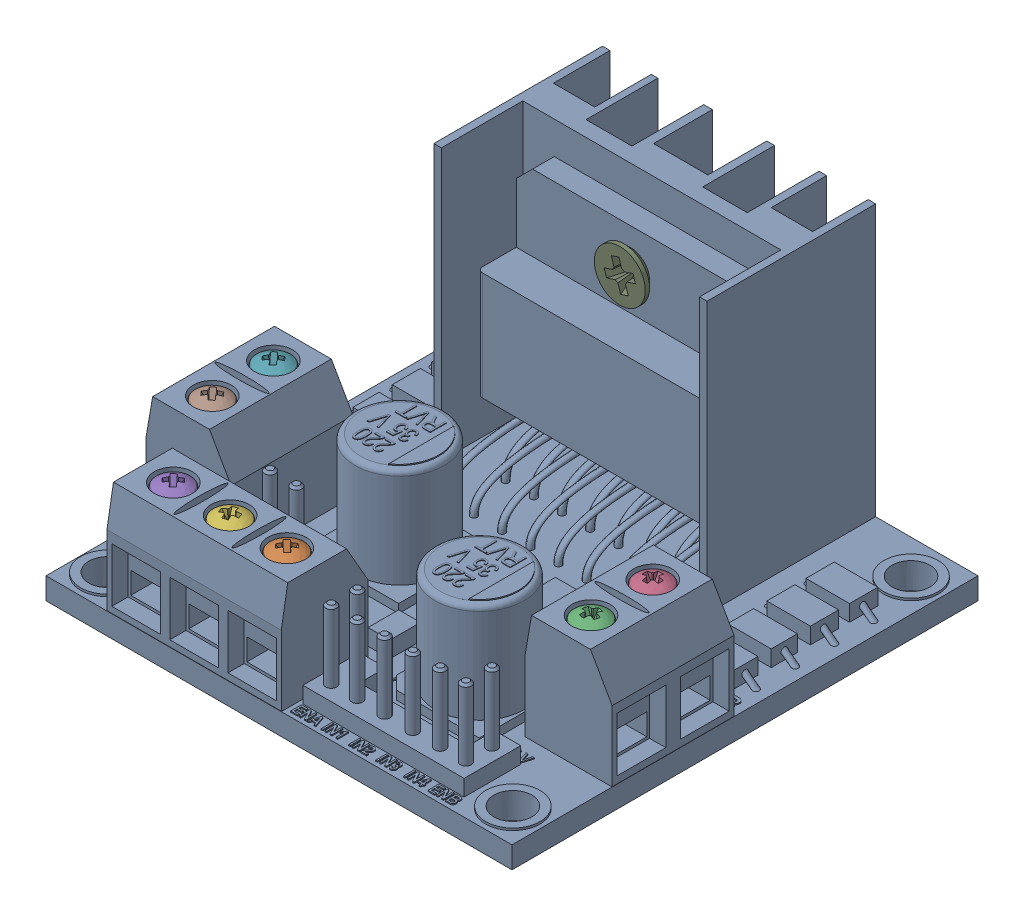
SolidWorks assembly L298N-2, configuration Varsayılan. Lengths in mm.
Overall size (43 28.01 43).
9 component instances, 3 part files, 0 mates.
Components (placement in the parent):
- L298N Stepper Motor Driver (Red)-Part File-1: L298N Stepper Motor Driver (Red)-Part File [Varsayılan] at (16.8606 10.1012 32.1341) size (43 28.01 43)
- pan head cross recess screw_iso_ISO 7045 - M1.6 x 4 - Z - 4N-1: pan head cross recess screw_iso_ISO 7045 - M1.6 x 4 - Z - 4N [Varsayılan] at (14.2688 22.4012 50.3107) x (0 -1 0) z (0.720108 0 0.693862) size (5.3 3.2 3.23)
- pan head cross recess screw_iso_ISO 7045 - M1.6 x 4 - Z - 4N-2: pan head cross recess screw_iso_ISO 7045 - M1.6 x 4 - Z - 4N [Varsayılan] at (33.6606 22.4012 41.6421) x (0 -1 0) z (-0.222944 0 0.974831) size (5.3 3.2 3.23)
- pan head cross recess screw_iso_ISO 7045 - M1.6 x 4 - Z - 4N-3: pan head cross recess screw_iso_ISO 7045 - M1.6 x 4 - Z - 4N [Varsayılan] at (33.6606 22.4012 35.9476) x (0 -1 0) z (0 0 1) size (5.3 3.2 3.23)
- pan head cross recess screw_iso_ISO 7045 - M1.6 x 4 - Z - 4N-4: pan head cross recess screw_iso_ISO 7045 - M1.6 x 4 - Z - 4N [Varsayılan] at (3.7852 22.4012 50.3107) x (0 -1 0) z (0.734198 0 -0.678936) size (5.3 3.2 3.23)
- pan head cross recess screw_iso_ISO 7045 - M1.6 x 4 - Z - 4N-5: pan head cross recess screw_iso_ISO 7045 - M1.6 x 4 - Z - 4N [Varsayılan] at (9.027 22.4012 50.3107) x (0 -1 0) z (0.308372 0 0.951266) size (5.3 3.2 3.23)
- pan head cross recess screw_iso_ISO 7045 - M1.6 x 4 - Z - 4N-6: pan head cross recess screw_iso_ISO 7045 - M1.6 x 4 - Z - 4N [Varsayılan] at (-1.3394 22.4012 35.9476) x (0 -1 0) z (-0.742963 0 0.669332) size (5.3 3.2 3.23)
- pan head cross recess screw_iso_ISO 7045 - M1.6 x 4 - Z - 4N-7: pan head cross recess screw_iso_ISO 7045 - M1.6 x 4 - Z - 4N [Varsayılan] at (-1.3394 22.4012 41.5921) x (0 -1 0) z (-0.751552 0 0.659674) size (5.3 3.2 3.23)
- countersunk flat head cross recess screw_iso_ISO 7046-1 - M2.5 x 3 - Z - 3N-1: countersunk flat head cross recess screw_iso_ISO 7046-1 - M2.5 x 3 - Z - 3N [Varsayılan] at (16.3567 30.6012 21.6857) x (0 0 -1) z (-0.309066 0.951041 0) size (3 4.7 4.7)
